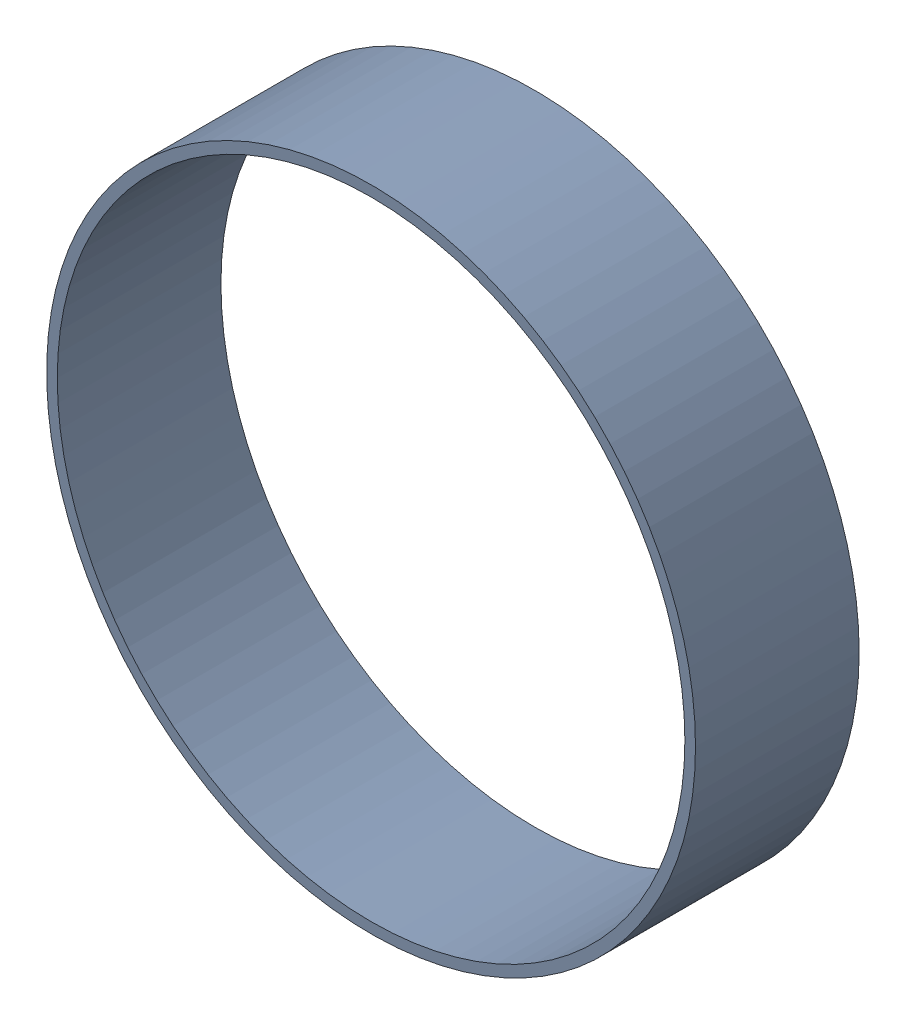
SolidWorks assembly Pad Free-4(36.068mm,1.016mm) on Multi-Layer, configuration Predeterminado. Lengths in mm.
Overall size (1.55 1.55 0.39).
2 component instances, 1 part files, 0 mates.
Components (placement in the parent):
- Pad Hole-2-1: Pad Hole-2 [Predeterminado] at (36.068 1.016 -0.4013) size (1.55 1.55 0.39)
  - Pad Hole-Part-1-2-1: Pad Hole-Part-1-2 [Predeterminado] at origin size (1.55 1.55 0.39)
